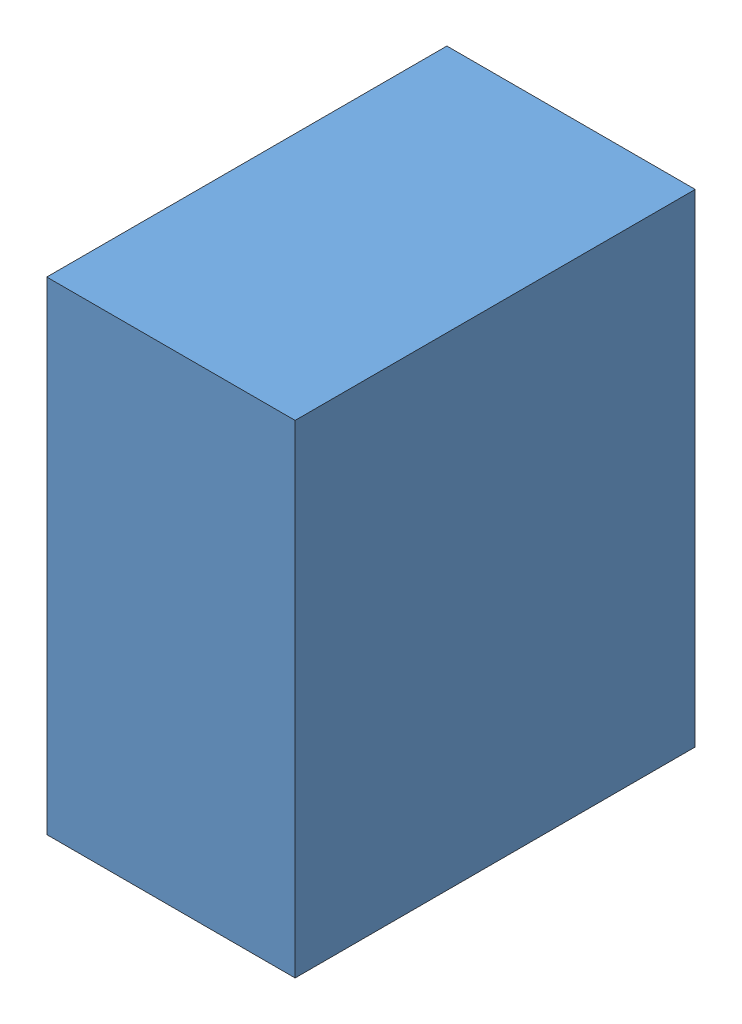
SolidWorks assembly ALEX, configuration Standard. Lengths in mm.
Overall size (360 700 580).
6 component instances, 3 part files, 15 mates.
Components (placement in the parent):
- Alex-Korpus-1: Alex-Korpus [Standard] at (-110.9342 320.3554 700) size (360 700 580)
- Alex-Schublade-Hoch-1: Alex-Schublade-Hoch [Standard] at (-110.9342 -359.6446 410) size (340 150 570)
- Alex-Schublade-Hoch-2: Alex-Schublade-Hoch [Standard] at (-110.9342 -209.6446 410) size (340 150 570)
- Alex-Schublade-Hoch-3: Alex-Schublade-Hoch [Standard] at (-110.9342 -59.6446 410) size (340 150 570)
- Alex-Schublade-Tief-1: Alex-Schublade-Tief [Standard] at (-110.9342 90.3554 410) size (340 115 570)
- Alex-Schublade-Tief-2: Alex-Schublade-Tief [Standard] at (-110.9342 205.3554 410) size (340 115 570)
Mates (geometry in assembly coordinates):
- Deckungsgleich1: coincident anti-aligned: plane of Alex-Korpus-1 through (-280.9342 -359.6446 980) normal (0 0 -1); plane of Alex-Schublade-Tief-2 through (-110.9342 205.3554 980) normal (0 0 1)
- Deckungsgleich2: coincident anti-aligned: plane of Alex-Korpus-1 through (-280.9342 -359.6446 980) normal (0 0 -1); plane of Alex-Schublade-Tief-1 through (-110.9342 90.3554 980) normal (0 0 1)
- Deckungsgleich3: coincident anti-aligned: plane of Alex-Korpus-1 through (-280.9342 -359.6446 980) normal (0 0 -1); plane of Alex-Schublade-Hoch-3 through (-110.9342 -59.6446 980) normal (0 0 1)
- Deckungsgleich4: coincident anti-aligned: plane of Alex-Korpus-1 through (-280.9342 -359.6446 980) normal (0 0 -1); plane of Alex-Schublade-Hoch-2 through (-110.9342 -209.6446 980) normal (0 0 1)
- Deckungsgleich5: coincident: plane of Alex-Korpus-1 through (-280.9342 -359.6446 980) normal (0 0 -1); plane of Alex-Schublade-Hoch-1 through (-110.9342 -359.6446 980) normal (0 0 1)
- Deckungsgleich6: coincident anti-aligned: plane of Alex-Korpus-1 through (59.0658 -359.6446 980) normal (-1 0 0); plane of Alex-Schublade-Hoch-1 through (59.0658 -359.6446 420) normal (1 0 0)
- Deckungsgleich7: coincident: plane of Alex-Korpus-1 through (59.0658 -359.6446 980) normal (-1 0 0); plane of Alex-Schublade-Hoch-2 through (59.0658 -209.6446 420) normal (1 0 0)
- Deckungsgleich8: coincident: plane of Alex-Korpus-1 through (59.0658 -359.6446 980) normal (-1 0 0); plane of Alex-Schublade-Hoch-3 through (59.0658 -59.6446 420) normal (1 0 0)
- Deckungsgleich9: coincident anti-aligned: plane of Alex-Korpus-1 through (59.0658 -359.6446 980) normal (-1 0 0); plane of Alex-Schublade-Tief-1 through (59.0658 90.3554 420) normal (1 0 0)
- Deckungsgleich10: coincident: plane of Alex-Korpus-1 through (59.0658 -359.6446 980) normal (-1 0 0); plane of Alex-Schublade-Tief-2 through (59.0658 205.3554 420) normal (1 0 0)
- Deckungsgleich11: coincident anti-aligned: plane of Alex-Korpus-1 through (-110.9342 -359.6446 700) normal (0 1 0); plane of Alex-Schublade-Hoch-1 through (-280.9342 -359.6446 420) normal (0 -1 0)
- Deckungsgleich12: coincident anti-aligned: plane of Alex-Schublade-Hoch-1 through (-280.9342 -209.6446 420) normal (0 1 0); plane of Alex-Schublade-Hoch-2 through (-280.9342 -209.6446 420) normal (0 -1 0)
- Deckungsgleich13: coincident anti-aligned: plane of Alex-Schublade-Hoch-2 through (-280.9342 -59.6446 420) normal (0 1 0); plane of Alex-Schublade-Hoch-3 through (-280.9342 -59.6446 420) normal (0 -1 0)
- Deckungsgleich14: coincident anti-aligned: plane of Alex-Schublade-Hoch-3 through (-280.9342 90.3554 420) normal (0 1 0); plane of Alex-Schublade-Tief-1 through (-280.9342 90.3554 420) normal (0 -1 0)
- Deckungsgleich15: coincident anti-aligned: plane of Alex-Schublade-Tief-1 through (-280.9342 205.3554 420) normal (0 1 0); plane of Alex-Schublade-Tief-2 through (-280.9342 205.3554 420) normal (0 -1 0)
